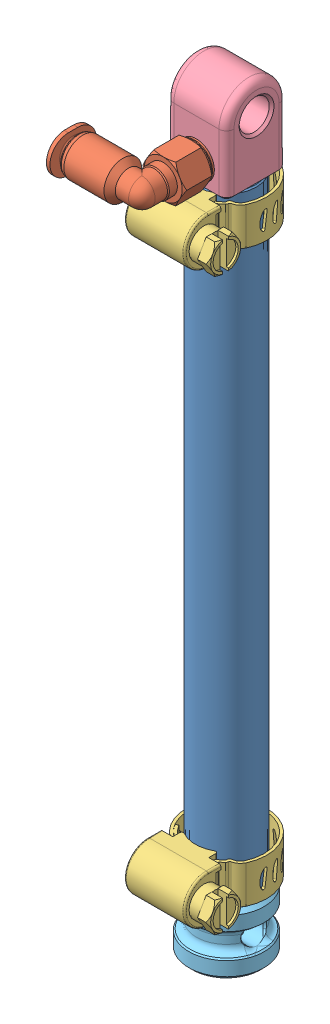
SolidWorks assembly AARL_QR_PN_PA_FR_SH_FL-Flexor, configuration Default. Lengths in mm.
Overall size (26.6 161.92 31.28).
6 component instances, 5 part files, 15 mates.
Components (placement in the parent):
- AARL_QR_PN_PA_FR_SH_FL_001-1: AARL_QR_PN_PA_FR_SH_FL_001 [Resting] at origin size (12.7 130.18 12.7)
- AARL_Puppy_18_02_57_010-QSML-M3-4-1: AARL_Puppy_18_02_57_010-QSML-M3-4 [Default] at (0 69.85 17.85) x (-1 0 0) z (0 0 -1) size (20.32 8 18.9)
- AARL_Puppy_18_02_57_011-5388K140_Hose-Clamp-1: AARL_Puppy_18_02_57_011-5388K140_Hose-Clamp [5388K14] at (0 -60.1345 0) x (1 0 0) z (0 -1 0) size (19.43 23.71 9.91)
- AARL_Puppy_18_02_57_011-5388K140_Hose-Clamp-2: AARL_Puppy_18_02_57_011-5388K140_Hose-Clamp [5388K14] at (0 60.1345 0) x (1 0 0) z (0 -1 0) size (19.43 23.71 9.91)
- AARL_QR_PN_EP_001-1: AARL_QR_PN_EP_001 [Default] at (0 77.7875 0) x (0 0 1) z (-1 0 0) size (12.7 31.75 12.7)
- AARL_QR_PN_EP_002-1: AARL_QR_PN_EP_002 [Default] at (0 -65.0875 0) x (-1 0 0) z (0 0 1) size (15.88 25.4 15.88)
Mates (geometry in assembly coordinates):
- Concentric1: concentric aligned: cylinder of AARL_QR_PN_PA_FR_SH_FL_001-1 through (0 11.6086 0) axis (0 1 0) radius 4.7625; cylinder of AARL_QR_PN_EP_001-1 through (0 87.3315 0) axis (0 1 0) radius 4.3656
- Parallel1: parallel aligned: plane of AARL_QR_PN_EP_001-1 through (-6.35 65.0875 6.35) normal (0 0 1)
- Coincident2: coincident anti-aligned: plane of AARL_QR_PN_PA_FR_SH_FL_001-1 through (4.7625 65.0875 0) normal (0 1 0); plane of AARL_QR_PN_EP_001-1 through (-6.35 65.0875 -6.35) normal (0 -1 0)
- Concentric2: concentric anti-aligned: cylinder of AARL_QR_PN_PA_FR_SH_FL_001-1 through (0 11.6086 0) axis (0 1 0) radius 4.7625; cylinder of AARL_QR_PN_EP_002-1 through (0 -72.8252 0) axis (0 -1 0) radius 4.3656
- Coincident3: coincident anti-aligned: plane of AARL_QR_PN_PA_FR_SH_FL_001-1 through (6.35 -65.0875 0) normal (0 -1 0); plane of AARL_QR_PN_EP_002-1 through (-4.3656 -65.0875 0) normal (0 1 0)
- Parallel2: parallel anti-aligned: cylinder of AARL_QR_PN_EP_001-1 through (-6.35 77.7875 0) axis (1 0 0) radius 3.175; cylinder of AARL_QR_PN_EP_002-1 through (7.9375 -71.4375 0) axis (-1 0 0) radius 2.3813
- Concentric4: concentric aligned: cylinder of AARL_Puppy_18_02_57_010-QSML-M3-4-1 through (0 69.85 6.35) axis (0 0 1) radius 1.5; cylinder of AARL_QR_PN_EP_001-1 through (0 69.85 6.35) axis (0 0 1) radius 2.0193
- Coincident4: coincident anti-aligned: plane of AARL_Puppy_18_02_57_010-QSML-M3-4-1 through (0 69.85 6.35) normal (0 0 -1); plane of AARL_QR_PN_EP_001-1 through (-6.35 65.0875 6.35) normal (0 0 1)
- Parallel3: parallel aligned: plane of AARL_Puppy_18_02_57_010-QSML-M3-4-1 through (2.3094 65.85 13.4056) normal (0 -1 0); plane of AARL_QR_PN_EP_001-1 through (-6.35 65.0875 -6.35) normal (0 -1 0)
- Concentric5: concentric aligned: cylinder of AARL_QR_PN_PA_FR_SH_FL_001-1 through (0 11.6086 0) axis (0 1 0) radius 6.35; cylinder of AARL_Puppy_18_02_57_011-5388K140_Hose-Clamp-2 through (0 56.1658 0) axis (0 1 0) radius 7.9375
- Coincident6: coincident aligned: plane of AARL_Puppy_18_02_57_011-5388K140_Hose-Clamp-2 through (6.35 60.1345 10.2337) normal (1 0 0); plane of AARL_QR_PN_EP_001-1 through (6.35 77.7875 0) normal (1 0 0)
- Coincident7: coincident anti-aligned: plane of AARL_Puppy_18_02_57_011-5388K140_Hose-Clamp-2 through (0 65.0875 0) normal (0 1 0); plane of AARL_QR_PN_EP_001-1 through (-6.35 65.0875 -6.35) normal (0 -1 0)
- Concentric6: concentric aligned: cylinder of AARL_QR_PN_PA_FR_SH_FL_001-1 through (0 11.6086 0) axis (0 1 0) radius 6.35; cylinder of AARL_Puppy_18_02_57_011-5388K140_Hose-Clamp-1 through (0 -64.1033 0) axis (0 1 0) radius 7.9375
- Coincident8: coincident aligned: plane of AARL_Puppy_18_02_57_011-5388K140_Hose-Clamp-1 through (6.35 -60.1345 10.2337) normal (1 0 0); plane of AARL_QR_PN_EP_001-1 through (6.35 77.7875 0) normal (1 0 0)
- Coincident9: coincident anti-aligned: plane of AARL_Puppy_18_02_57_011-5388K140_Hose-Clamp-1 through (0 -65.0875 0) normal (0 -1 0); plane of AARL_QR_PN_EP_002-1 through (-4.3656 -65.0875 0) normal (0 1 0)
